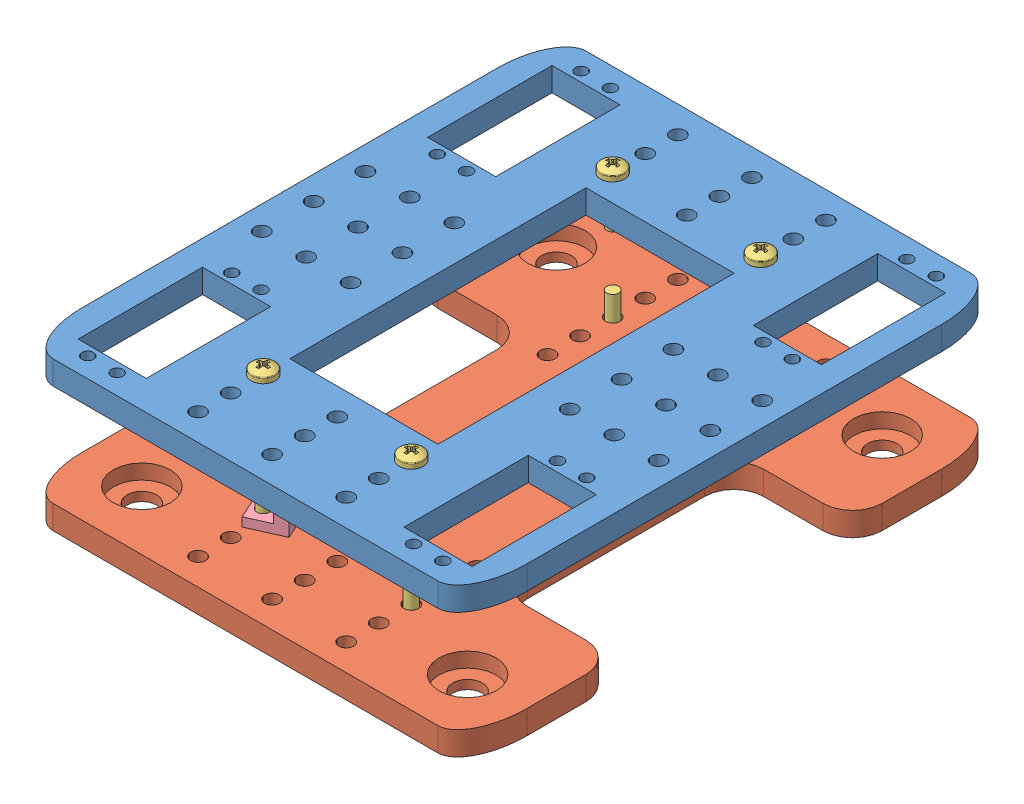
SolidWorks assembly 3423Model_Spider_OfDinh_Body_ASM, configuration Default. Lengths in mm.
Overall size (150.2 56.34 180.2).
11 component instances, 4 part files, 24 mates.
Components (placement in the parent):
- 3423Model_Spider_OfDinh_Body_p1-1: 3423Model_Spider_OfDinh_Body_p1 [Default] at origin size (150.2 8.2 180.2)
- 3423Model_Spider_OfDinh_Body_p2-1: 3423Model_Spider_OfDinh_Body_p2 [Default] at (0 -42.3 0) size (150.2 8.2 180.2)
- pan head cross recess screw_iso-1: pan head cross recess screw_iso [ISO 7045 - M4 x 16 - Z - 16N] at (-25 7.1 59) x (0 -1 0) z (0 0 1) size (19.02 8 8)
- pan head cross recess screw_iso-2: pan head cross recess screw_iso [ISO 7045 - M4 x 16 - Z - 16N] at (25 7.1 59) x (0 -1 0) z (0 0 1) size (19.02 8 8)
- pan head cross recess screw_iso-3: pan head cross recess screw_iso [ISO 7045 - M4 x 16 - Z - 16N] at (-25 7.1 -59) x (0 -1 0) z (0 0 1) size (19.02 8 8)
- pan head cross recess screw_iso-4: pan head cross recess screw_iso [ISO 7045 - M4 x 16 - Z - 16N] at (25 7.1 -59) x (0 -1 0) z (0 0 1) size (19.02 8 8)
- pan head cross recess screw_iso-5: pan head cross recess screw_iso [ISO 7045 - M4 x 16 - Z - 16N] at (-25 -49.4 59) x (0 1 0) z (0 0 1) size (19.02 8 8)
- pan head cross recess screw_iso-6: pan head cross recess screw_iso [ISO 7045 - M4 x 16 - Z - 16N] at (25 -49.4 59) x (0 1 0) z (0 0 1) size (19.02 8 8)
- pan head cross recess screw_iso-7: pan head cross recess screw_iso [ISO 7045 - M4 x 16 - Z - 16N] at (-25 -49.4 -59) x (0 1 0) z (0 0 1) size (19.02 8 8)
- pan head cross recess screw_iso-8: pan head cross recess screw_iso [ISO 7045 - M4 x 16 - Z - 16N] at (25 -49.4 -59) x (0 1 0) z (0 0 1) size (19.02 8 8)
- 3423Model_Spider_OfDinh_Body_p3-1: 3423Model_Spider_OfDinh_Body_p3 [Default] at (-22.7191 -21.3 57.9765) x (-0.912357 0 0.409395) z (-0.409395 0 -0.912357) size (12 34 10)
Mates (geometry in assembly coordinates):
- Coincident1: coincident aligned: plane of 3423Model_Spider_OfDinh_Body_p1-1 through (0 0 0) normal (1 0 0)
- Coincident2: coincident aligned: plane of 3423Model_Spider_OfDinh_Body_p1-1 through (0 0 0) normal (0 0 1)
- Coincident3: coincident aligned: plane of 3423Model_Spider_OfDinh_Body_p1-1 through (0 0 0) normal (0 1 0)
- Coincident4: coincident aligned: plane of 3423Model_Spider_OfDinh_Body_p2-1 through (0 -42.3 0) normal (1 0 0)
- Coincident5: coincident aligned: plane of 3423Model_Spider_OfDinh_Body_p2-1 through (0 -42.3 0) normal (0 0 1)
- Distance1: distance = 34.3 mm anti-aligned: plane of 3423Model_Spider_OfDinh_Body_p2-1 through (0 -38.3 0) normal (0 1 0); plane of 3423Model_Spider_OfDinh_Body_p1-1 through (0 -4 0) normal (0 -1 0)
- Concentric1: concentric aligned: cylinder of 3423Model_Spider_OfDinh_Body_p1-1 through (-25 -4.1 59) axis (0 1 0) radius 2.5; cylinder of pan head cross recess screw_iso-1 through (-25 32.5 59) axis (0 1 0) radius 4
- Coincident6: coincident anti-aligned: plane of 3423Model_Spider_OfDinh_Body_p1-1 through (0 4 0) normal (0 1 0); plane of pan head cross recess screw_iso-1 through (-23 4 59) normal (0 -1 0)
- Concentric2: concentric aligned: cylinder of 3423Model_Spider_OfDinh_Body_p1-1 through (25 -4.1 59) axis (0 1 0) radius 2.5; cylinder of pan head cross recess screw_iso-2 through (25 32.5 59) axis (0 1 0) radius 4
- Coincident7: coincident anti-aligned: plane of 3423Model_Spider_OfDinh_Body_p1-1 through (0 4 0) normal (0 1 0); plane of pan head cross recess screw_iso-2 through (27 4 59) normal (0 -1 0)
- Concentric3: concentric aligned: cylinder of 3423Model_Spider_OfDinh_Body_p1-1 through (-25 -4.1 -59) axis (0 1 0) radius 2.5; cylinder of pan head cross recess screw_iso-3 through (-25 32.5 -59) axis (0 1 0) radius 4
- Coincident8: coincident anti-aligned: plane of 3423Model_Spider_OfDinh_Body_p1-1 through (0 4 0) normal (0 1 0); plane of pan head cross recess screw_iso-3 through (-23 4 -59) normal (0 -1 0)
- Concentric4: concentric aligned: cylinder of 3423Model_Spider_OfDinh_Body_p1-1 through (25 -4.1 -59) axis (0 1 0) radius 2.5; cylinder of pan head cross recess screw_iso-4 through (25 32.5 -59) axis (0 1 0) radius 4
- Coincident9: coincident anti-aligned: plane of 3423Model_Spider_OfDinh_Body_p1-1 through (0 4 0) normal (0 1 0); plane of pan head cross recess screw_iso-4 through (27 4 -59) normal (0 -1 0)
- Concentric5: concentric anti-aligned: cylinder of 3423Model_Spider_OfDinh_Body_p2-1 through (-25 -46.4 59) axis (0 1 0) radius 2.5; cylinder of pan head cross recess screw_iso-5 through (-25 -74.8 59) axis (0 -1 0) radius 4
- Coincident10: coincident anti-aligned: plane of 3423Model_Spider_OfDinh_Body_p2-1 through (0 -46.3 0) normal (0 -1 0); plane of pan head cross recess screw_iso-5 through (-27 -46.3 59) normal (0 1 0)
- Concentric6: concentric anti-aligned: cylinder of 3423Model_Spider_OfDinh_Body_p2-1 through (25 -46.4 59) axis (0 1 0) radius 2.5; cylinder of pan head cross recess screw_iso-6 through (25 -74.8 59) axis (0 -1 0) radius 4
- Coincident11: coincident anti-aligned: plane of 3423Model_Spider_OfDinh_Body_p2-1 through (0 -46.3 0) normal (0 -1 0); plane of pan head cross recess screw_iso-6 through (23 -46.3 59) normal (0 1 0)
- Concentric7: concentric anti-aligned: cylinder of 3423Model_Spider_OfDinh_Body_p2-1 through (-25 -46.4 -59) axis (0 1 0) radius 2.5; cylinder of pan head cross recess screw_iso-7 through (-25 -74.8 -59) axis (0 -1 0) radius 4
- Coincident12: coincident anti-aligned: plane of 3423Model_Spider_OfDinh_Body_p2-1 through (0 -46.3 0) normal (0 -1 0); plane of pan head cross recess screw_iso-7 through (-27 -46.3 -59) normal (0 1 0)
- Concentric8: concentric anti-aligned: cylinder of 3423Model_Spider_OfDinh_Body_p2-1 through (25 -46.4 -59) axis (0 1 0) radius 2.5; cylinder of pan head cross recess screw_iso-8 through (25 -74.8 -59) axis (0 -1 0) radius 4
- Coincident13: coincident anti-aligned: plane of 3423Model_Spider_OfDinh_Body_p2-1 through (0 -46.3 0) normal (0 -1 0); plane of pan head cross recess screw_iso-8 through (23 -46.3 -59) normal (0 1 0)
- Concentric9: concentric anti-aligned: cylinder of pan head cross recess screw_iso-5 through (-25 -74.8 59) axis (0 -1 0) radius 2; cylinder of 3423Model_Spider_OfDinh_Body_p3-1 through (-25 -38.3 59) axis (0 1 0) radius 2.15
- Coincident14: coincident anti-aligned: plane of 3423Model_Spider_OfDinh_Body_p2-1 through (0 -38.3 0) normal (0 1 0); plane of 3423Model_Spider_OfDinh_Body_p3-1 through (-30.2402 -38.3 55.8711) normal (0 -1 0)
